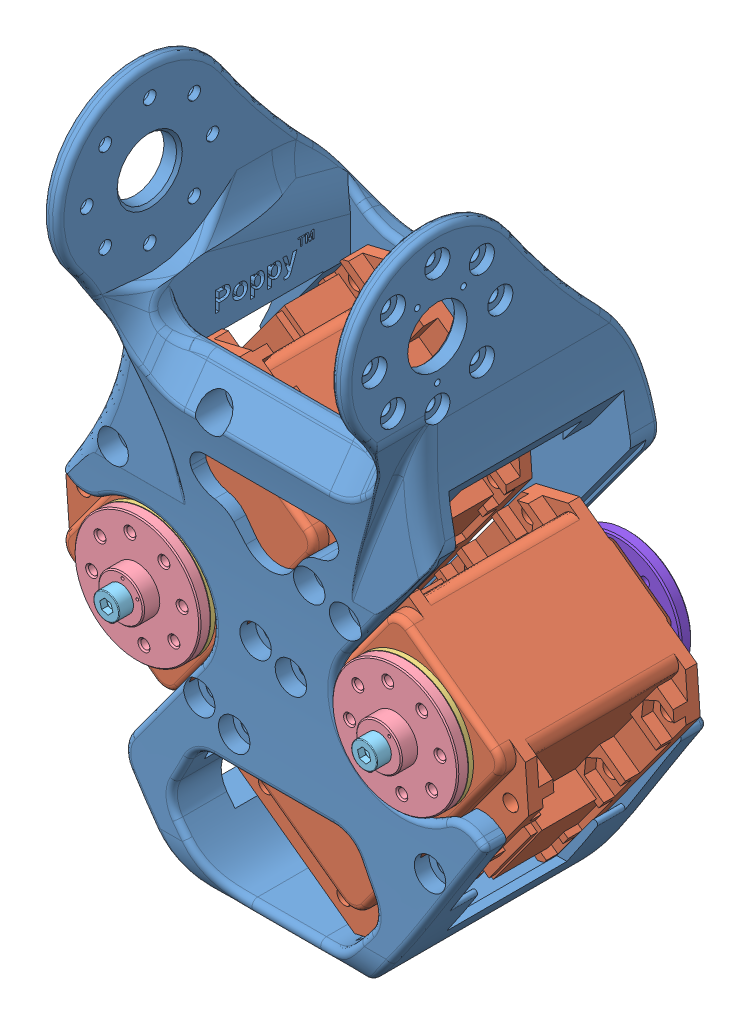
SolidWorks assembly pelvis, configuration Défaut. Lengths in mm.
Overall size (92.15 123.9 55.65).
19 component instances, 8 part files, 9 mates.
Components (placement in the parent):
- pelvis-1: pelvis [MX64_abs] at origin size (77.03 123.9 55.04)
- MX-28-1: MX-28 [U] at (-22.5417 0 0) x (-0.807391 0.590017 0) z (0 0 1) size (35.6 54.13 48.5)
  - dynamixel_x28series-1: dynamixel_x28series [U] at origin size (35.6 50.71 41.85)
  - trust_washer-1: trust_washer [U] at (0 0 18.6) x (-0.666375 -0.745617 0) z (0.745617 -0.666375 0) size (22 0.85 22)
  - HN07-N101-1: HN07-N101 [U] at (0 0 18.5) x (1 0 0) z (0 -1 0) size (22 5.85 22)
  - WB_M2.5x8-1: WB_M2.5x8 [ISO 4762 M2.5 x 8 --- 8N] at (0 0 25.85) x (0 0 -1) z (-0.991137 0.132843 0) size (10.5 4.5 4.5)
  - RX28-CAP-1: RX28-CAP [Défaut] at (0 0 -20.35) x (-0.995735 -0.092256 0) z (0 0 -1) size (7.2 7.2 1.8)
  - MF106ZZ-1: MF106ZZ [Défaut] at (0 0 -20.35) x (0.888333 -0.4592 0) z (-0.4592 -0.888333 0) size (11.2 3 11.2)
  - WB_M2.5x8-3: WB_M2.5x8 [ISO 4762 M2.5 x 8 --- 8N] at (0 0 -22.65) x (0 0 1) z (-0.936501 0.350665 0) size (10.5 4.5 4.5)
  - HN07-i101-1: HN07-i101 [Défaut] at (0 0 -20.5) x (1 0 0) z (0 1 0) size (22 3.05 22)
- MX-28-2: MX-28 [U] at (22.5417 0 0) x (0.807391 -0.590017 0) z (0 0 1) size (35.6 54.13 48.5)
  - dynamixel_x28series-1: dynamixel_x28series [U] at origin size (35.6 50.71 41.85)
  - trust_washer-1: trust_washer [U] at (0 0 18.6) x (-0.666375 -0.745617 0) z (0.745617 -0.666375 0) size (22 0.85 22)
  - HN07-N101-1: HN07-N101 [U] at (0 0 18.5) x (1 0 0) z (0 -1 0) size (22 5.85 22)
  - WB_M2.5x8-1: WB_M2.5x8 [ISO 4762 M2.5 x 8 --- 8N] at (0 0 25.85) x (0 0 -1) z (-0.991137 0.132843 0) size (10.5 4.5 4.5)
  - RX28-CAP-1: RX28-CAP [Défaut] at (0 0 -20.35) x (-0.995735 -0.092256 0) z (0 0 -1) size (7.2 7.2 1.8)
  - MF106ZZ-1: MF106ZZ [Défaut] at (0 0 -20.35) x (0.888333 -0.4592 0) z (-0.4592 -0.888333 0) size (11.2 3 11.2)
  - WB_M2.5x8-3: WB_M2.5x8 [ISO 4762 M2.5 x 8 --- 8N] at (0 0 -22.65) x (0 0 1) z (-0.936501 0.350665 0) size (10.5 4.5 4.5)
  - HN07-i101-1: HN07-i101 [Défaut] at (0 0 -20.5) x (1 0 0) z (0 1 0) size (22 3.05 22)
Mates (geometry in assembly coordinates):
- Coincident1: coincident aligned: line of pelvis-1 through (-22.5417 0 0) axis (0 0 1); line of MX-28-1/dynamixel_x28series-1 through (-22.5417 0 -27.2811) axis (0 0 1)
- Coincident2: coincident aligned: line of pelvis-1 through (22.5417 0 0) axis (0 0 1); line of MX-28-2/dynamixel_x28series-1 through (22.5417 0 -27.2811) axis (0 0 1)
- Coincident3: coincident aligned: plane of pelvis-1 through (0 0 0) normal (0 0 1); plane of MX-28-1/dynamixel_x28series-1 through (-22.5417 0 0) normal (0 0 1)
- Coincident4: coincident anti-aligned: plane of pelvis-1 through (-14.6945 10.7383 0) normal (0.807391 -0.590017 0); plane of MX-28-1/dynamixel_x28series-1
- Coincident5: coincident aligned: plane of pelvis-1 through (0 0 0) normal (0 0 1); plane of MX-28-2/dynamixel_x28series-1 through (22.5417 0 0) normal (0 0 1)
- Coincident6: coincident aligned: plane of pelvis-1 through (14.6945 -10.7383 0) normal (0.807391 -0.590017 0); plane of MX-28-2/dynamixel_x28series-1
- Coincident7: coincident aligned: plane of pelvis-1 through (0 0 0) normal (0 0 1); plane of assembly through (0 0 0) normal (0 0 1)
- Coincident8: coincident aligned: plane of pelvis-1 through (0 0 0) normal (0 1 0); plane of assembly through (0 0 0) normal (0 1 0)
- Coincident9: coincident aligned: plane of pelvis-1 through (0 0 0) normal (1 0 0); plane of assembly through (0 0 0) normal (1 0 0)
